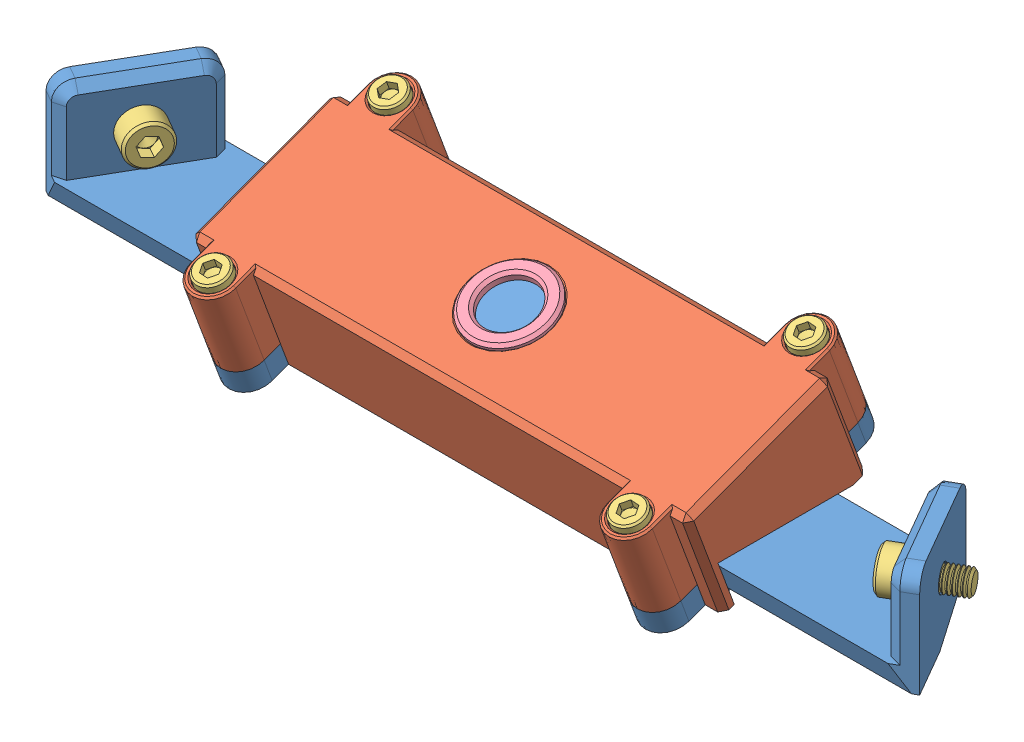
SolidWorks assembly Camera Assembly, configuration Default. Lengths in mm.
Overall size (156.29 32.1 140.07).
9 component instances, 4 part files, 17 mates.
Components (placement in the parent):
- Camera Mount-1: Camera Mount [Default] at (23.6651 -4 -152.5692) x (-0.5 0 0.866025) z (-0.866025 0 -0.5) size (86.35 23.97 130.57)
- Camera Housing-2: Camera Housing [Default] at (66.6151 1.6747 -25.5117) x (-1 0 0) z (0 0.347985 -0.9375) size (85.9 18.4 40.3)
- socket head cap screw_am-1: socket head cap screw_am [B18.3.1M - 3 x 0.5 x 16 Hex SHCS -- 16SHX] at (-12.2849 20.9061 -21.5733) x (0 -0.9375 -0.347985) z (0.347985 -0.326236 0.878906) size (19 5.5 5.5)
- socket head cap screw_am-2: socket head cap screw_am [B18.3.1M - 3 x 0.5 x 16 Hex SHCS -- 16SHX] at (-12.2849 9.5618 8.9892) x (0 -0.9375 -0.347985) z (-0.058173 -0.347396 0.935912) size (19 5.5 5.5)
- socket head cap screw_am-3: socket head cap screw_am [B18.3.1M - 3 x 0.5 x 16 Hex SHCS -- 16SHX] at (59.6151 20.9061 -21.5733) x (0 -0.9375 -0.347985) z (-0.058173 -0.347396 0.935912) size (19 5.5 5.5)
- socket head cap screw_am-4: socket head cap screw_am [B18.3.1M - 3 x 0.5 x 16 Hex SHCS -- 16SHX] at (59.6151 9.5618 8.9892) x (0 -0.9375 -0.347985) z (-0.058173 -0.347396 0.935912) size (19 5.5 5.5)
- socket head cap screw_am-5: socket head cap screw_am [B18.3.1M - 4 x 0.7 x 8 Hex SHCS -- 8SHX] at (-39.3061 6 -7.5) x (-0.866025 0 -0.5) z (0.09665 0.98114 -0.167404) size (12 7 7)
- socket head cap screw_am-6: socket head cap screw_am [B18.3.1M - 4 x 0.7 x 8 Hex SHCS -- 8SHX] at (86.6362 6 -7.5) x (0.866025 0 -0.5) z (0.5 0 0.866025) size (12 7 7)
- Camera Bezel-1: Camera Bezel [Default] at (23.6651 14.9996 -6.3791) x (-0.678869 0.255512 -0.688369) z (-0.73426 -0.236236 0.636439) size (14 2 14)
Mates (geometry in assembly coordinates):
- Concentric3: concentric: cylinder of Camera Mount-1 through (59.6151 2.7186 -28.3242) axis (0 0.9375 0.347985) radius 1.25; cylinder of Camera Housing-2 through (59.6151 2.7186 -28.3242) axis (0 0.9375 0.347985) radius 1.65
- Concentric4: concentric: cylinder of Camera Mount-1 through (-12.2849 -8.6257 2.2383) axis (0 0.9375 0.347985) radius 1.25; cylinder of Camera Housing-2 through (-12.2849 -8.6257 2.2383) axis (0 0.9375 0.347985) radius 1.65
- Coincident7: coincident: plane of Camera Mount-1 through (23.6651 46.1883 -133.9401) normal (0 0.9375 0.347985); plane of Camera Housing-2 through (66.6151 5.4247 -24.1198) normal (0 -0.9375 -0.347985)
- Concentric5: concentric: cylinder of Camera Housing-2 through (-12.2849 18.0936 -22.6173) axis (0 0.9375 0.347985) radius 2.85; cylinder of socket head cap screw_am-1 through (-12.2849 50.6718 -10.5248) axis (0 0.9375 0.347985) radius 2.75
- Concentric6: concentric: cylinder of Camera Housing-2 through (-12.2849 6.7493 7.9452) axis (0 0.9375 0.347985) radius 2.85; cylinder of socket head cap screw_am-2 through (-12.2849 39.3274 20.0377) axis (0 0.9375 0.347985) radius 2.75
- Concentric7: concentric: cylinder of Camera Housing-2 through (59.6151 18.0936 -22.6173) axis (0 0.9375 0.347985) radius 2.85; cylinder of socket head cap screw_am-3 through (59.6151 50.6718 -10.5248) axis (0 0.9375 0.347985) radius 2.75
- Concentric8: concentric: cylinder of Camera Housing-2 through (59.6151 6.7493 7.9452) axis (0 0.9375 0.347985) radius 2.85; cylinder of socket head cap screw_am-4 through (59.6151 39.3274 20.0377) axis (0 0.9375 0.347985) radius 2.75
- Coincident8: coincident: plane of Camera Housing-2 through (-12.2849 18.0936 -22.6173) normal (0 0.9375 0.347985); plane of socket head cap screw_am-1 through (-9.7068 18.4266 -23.5144) normal (0 -0.9375 -0.347985)
- Coincident9: coincident: plane of Camera Housing-2 through (59.6151 18.0936 -22.6173) normal (0 0.9375 0.347985); plane of socket head cap screw_am-3 through (62.3604 18.038 -22.4673) normal (0 -0.9375 -0.347985)
- Coincident10: coincident: plane of Camera Housing-2 through (59.6151 6.7493 7.9452) normal (0 0.9375 0.347985); plane of socket head cap screw_am-4 through (62.3604 6.6936 8.0952) normal (0 -0.9375 -0.347985)
- Coincident11: coincident: plane of Camera Housing-2 through (-12.2849 6.7493 7.9452) normal (0 0.9375 0.347985); plane of socket head cap screw_am-2 through (-9.5396 6.6936 8.0952) normal (0 -0.9375 -0.347985)
- Concentric9: concentric: cylinder of Camera Mount-1 through (-37.565 6 -6.4948) axis (-0.866025 0 -0.5) radius 2.125; cylinder of socket head cap screw_am-5 through (-11.8097 6 8.375) axis (0.866025 0 0.5) radius 3.5
- Concentric10: concentric: cylinder of Camera Mount-1 through (84.8952 6 -6.4948) axis (0.866025 0 -0.5) radius 2.125; cylinder of socket head cap screw_am-6 through (59.1399 6 8.375) axis (-0.866025 0 0.5) radius 3.5
- Coincident12: coincident: plane of Camera Mount-1 through (83.4608 14 -21) normal (-0.866025 0 0.5); plane of socket head cap screw_am-6 through (90.1003 9.5 -9.5) normal (0.866025 0 -0.5)
- Coincident13: coincident: plane of Camera Mount-1 through (-48.255 14 0) normal (0.866025 0 0.5); plane of socket head cap screw_am-5 through (-44.4872 6.6766 -6.5261) normal (-0.866025 0 -0.5)
- Concentric11: concentric: cylinder of Camera Housing-2 through (23.6651 -2.9535 -13.043) axis (0 0.9375 0.347985) radius 5.75; cylinder of Camera Bezel-1 through (23.6651 13.1246 -7.075) axis (0 0.9375 0.347985) radius 4.5
- Coincident14: coincident: cone of Camera Housing-2 through (23.6651 12.8902 -7.162) axis (0 -0.9375 -0.347985); cone of Camera Bezel-1 through (23.6651 13.1246 -7.075) axis (0 -0.9375 -0.347985)
